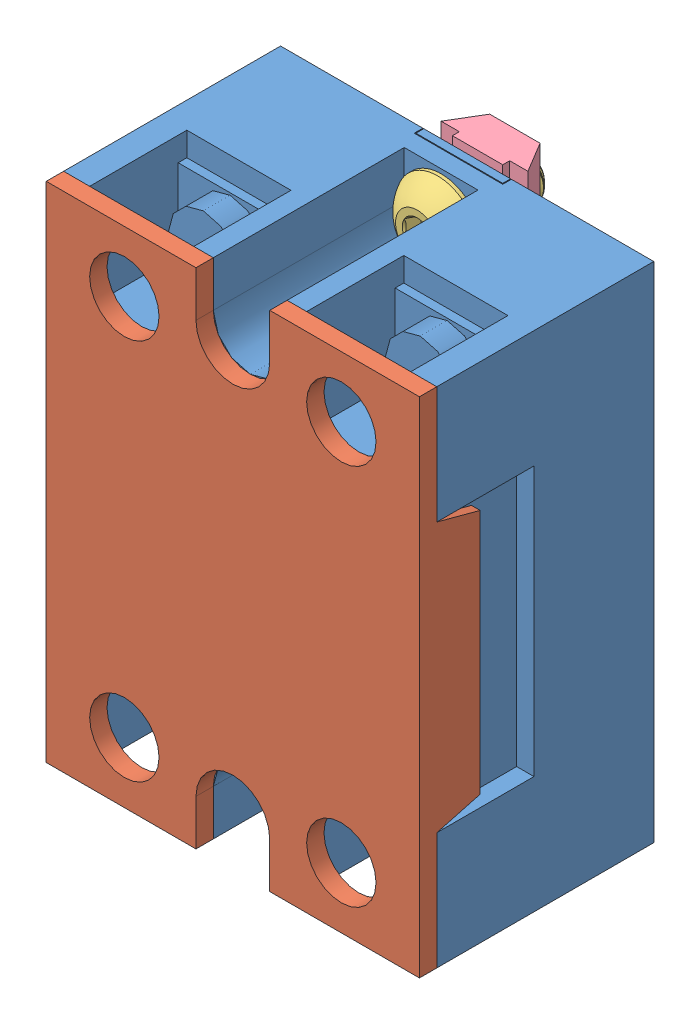
SolidWorks assembly G3NA_220B, configuration Default. Lengths in mm.
Overall size (43 58 34.28).
6 component instances, 4 part files, 13 mates.
Components (placement in the parent):
- G3NA_220B_BASE-1: G3NA_220B_BASE [Default] at origin size (43 58 25)
- G3NA_220B_COVER-1: G3NA_220B_COVER [Default] at (0 -23.75 27) size (43 58 7)
- 5mmX10mm_Buttonhead(McMaster_91239A224)-1: 5mmX10mm_Buttonhead(McMaster_91239A224) [91239A224] at (0 0 5.75) size (9.5 9.5 13.21)
- 5mmX10mm_Buttonhead(McMaster_91239A224)-2: 5mmX10mm_Buttonhead(McMaster_91239A224) [91239A224] at (0 -47.5 5.75) size (9.5 9.5 13.21)
- HNTTSN5-5-1: HNTTSN5-5 [Default] at (0 0 -1.2) x (0 0 1) z (0 1 0) size (4.3 10 10)
- HNTTSN5-5-2: HNTTSN5-5 [Default] at (0 -47.5 -1.2) x (0 0 1) z (0 1 0) size (4.3 10 10)
Mates (geometry in assembly coordinates):
- Coincident1: coincident aligned: plane of G3NA_220B_BASE-1 through (21.5 5.25 13.8) normal (1 0 0); plane of G3NA_220B_COVER-1 through (21.5 5.25 25) normal (1 0 0)
- Coincident2: coincident aligned: plane of G3NA_220B_BASE-1 through (-21.5 5.25 13.8) normal (0 1 0); plane of G3NA_220B_COVER-1 through (4.25 5.25 25) normal (0 1 0)
- Coincident3: coincident anti-aligned: plane of G3NA_220B_BASE-1 through (0 -47.5 25) normal (0 0 1); plane of G3NA_220B_COVER-1 through (0 -47.5 25) normal (0 0 -1)
- Concentric1: concentric anti-aligned: cylinder of G3NA_220B_BASE-1 through (0 -47.5 13.8) axis (0 0 -1) radius 2.25; cylinder of 5mmX10mm_Buttonhead(McMaster_91239A224)-2 through (0 -47.5 5.75) axis (0 0 1) radius 4.75
- Coincident4: coincident anti-aligned: plane of G3NA_220B_BASE-1 through (0 -47.5 3) normal (0 0 1); plane of 5mmX10mm_Buttonhead(McMaster_91239A224)-2 through (0 -52.25 3) normal (0 0 -1)
- Concentric2: concentric anti-aligned: cylinder of G3NA_220B_BASE-1 through (0 0 13.8) axis (0 0 -1) radius 2.25; cylinder of 5mmX10mm_Buttonhead(McMaster_91239A224)-1 through (0 0 5.75) axis (0 0 1) radius 4.75
- Coincident5: coincident anti-aligned: plane of G3NA_220B_BASE-1 through (0 -47.5 3) normal (0 0 1); plane of 5mmX10mm_Buttonhead(McMaster_91239A224)-1 through (0 -4.75 3) normal (0 0 -1)
- Concentric3: concentric anti-aligned: cylinder of 5mmX10mm_Buttonhead(McMaster_91239A224)-1 through (0 0 5.75) axis (0 0 1) radius 4.75; cylinder of HNTTSN5-5-1 through (0 0 -1.2) axis (0 0 -1) radius 2.067
- Concentric4: concentric anti-aligned: cylinder of 5mmX10mm_Buttonhead(McMaster_91239A224)-2 through (0 -47.5 5.75) axis (0 0 1) radius 4.75; cylinder of HNTTSN5-5-2 through (0 -47.5 -1.2) axis (0 0 -1) radius 2.067
- Parallel1: parallel anti-aligned: plane of G3NA_220B_BASE-1 through (-21.5 -52.75 13.8) normal (0 -1 0); plane of HNTTSN5-5-2 through (0 -42.5 -1.2) normal (0 1 0)
- Parallel2: parallel anti-aligned: plane of G3NA_220B_BASE-1 through (-21.5 -52.75 13.8) normal (0 -1 0); plane of HNTTSN5-5-1 through (0 5 -1.2) normal (0 1 0)
- Distance4: distance = 2 mm anti-aligned: plane of HNTTSN5-5-2 through (-5 -42.5 -2) normal (0 0 1); plane of G3NA_220B_BASE-1 through (0 -47.5 0) normal (0 0 -1)
- Distance5: distance = 2 mm anti-aligned: plane of G3NA_220B_BASE-1 through (0 -47.5 0) normal (0 0 -1); plane of HNTTSN5-5-1 through (-5 5 -2) normal (0 0 1)
